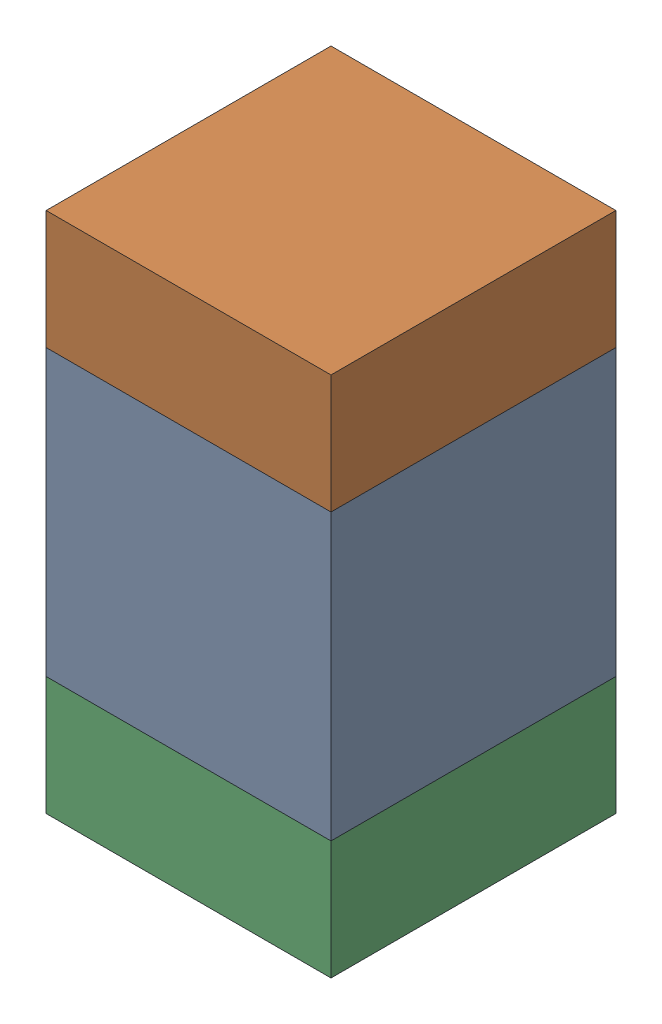
SolidWorks assembly C409PCB, configuration Default. Lengths in mm.
Overall size (0.6 1.1 0.6).
6 component instances, 2 part files, 0 mates.
Components (placement in the parent):
- 761606048-1: 761606048 [Default] at (123.1 104 0) size (0.6 0.6 0.6)
  - Extruded_9-1: Extruded_9 [Default] at origin size (0.6 0.6 0.6)
- 854785296-1: 854785296 [Default] at (123.1 104.425 0) size (0.6 0.25 0.6)
  - Extruded_10-1: Extruded_10 [Default] at origin size (0.6 0.25 0.6)
- 854785296-2: 854785296 [Default] at (123.1 103.575 0) size (0.6 0.25 0.6)
  - Extruded_10-1: Extruded_10 [Default] at origin size (0.6 0.25 0.6)
